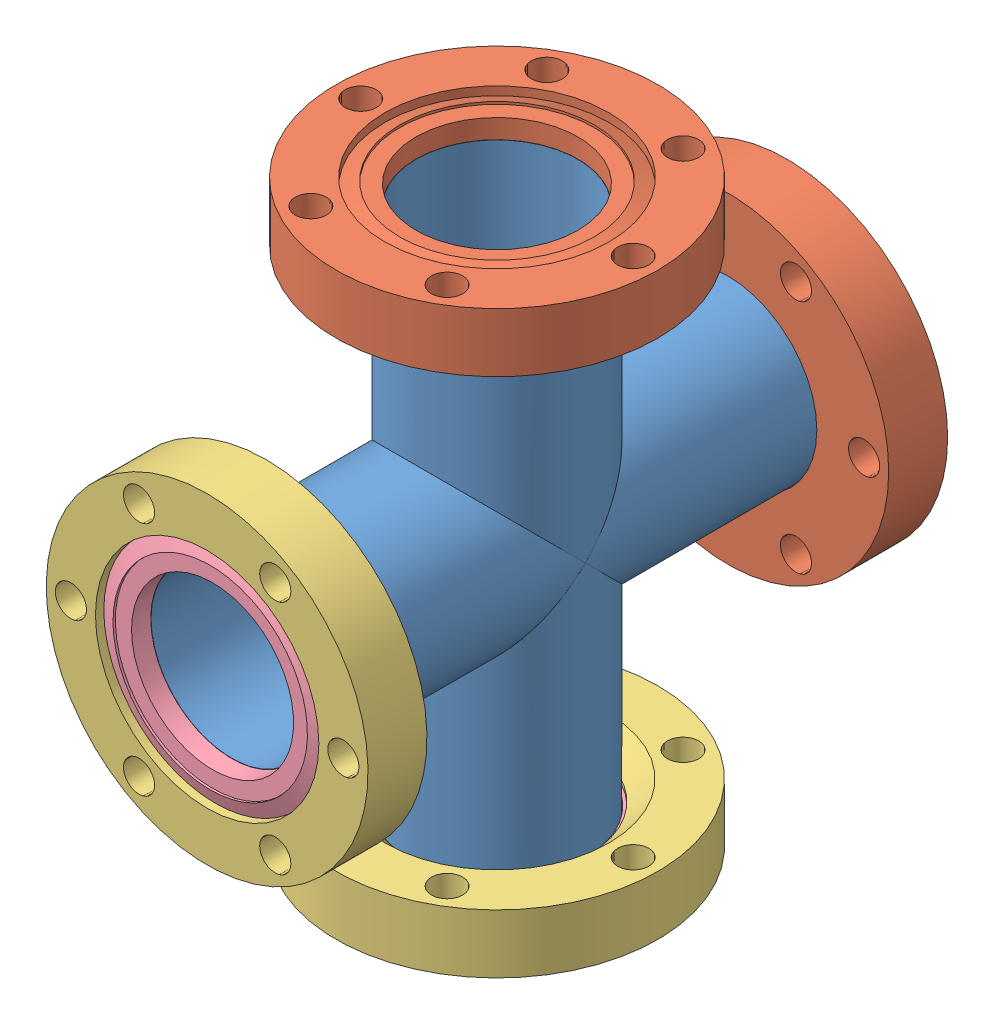
SolidWorks assembly Ion Gauge Nipple, configuration Default. Lengths in mm.
Overall size (69.34 124.92 124.92).
10 component instances, 4 part files, 0 mates.
Components (placement in the parent):
- 405002 P1_405002-001-1: 405002 P1_405002-001 [Default] at origin size (38.83 38.83 115)
- 405002 P1_405002-001-2: 405002 P1_405002-001 [Default] at (0 -57.15 57.15) x (1 0 0) z (0 1 0) size (38.83 38.83 115)
- 405002 P2_110014 (2.75 X 1.5 NR)_1-1: 405002 P2_110014 (2.75 X 1.5 NR)_1 [Default] at (0 56.1086 57.15) x (0 1 0) z (1 0 0) size (12.7 69.34 69.34)
- 405002 P2_110014 (2.75 X 1.5 NR)_1-2: 405002 P2_110014 (2.75 X 1.5 NR)_1 [Default] at (0 0 1.0414) x (0 0 -1) z (1 0 0) size (12.7 69.34 69.34)
- 405002 P3_100014 (2.75 X 1.5 R)_1-1: 405002 P3_100014 (2.75 X 1.5 R)_1 [Default] at (0 0 119.6086) x (0 0 -1) z (1 0 0) size (12.7 69.34 69.34)
  - 405002 P4_100014 (2.75 X 1.5 REC)_1-1: 405002 P4_100014 (2.75 X 1.5 REC)_1 [Default] at origin size (12.7 69.34 69.34)
  - 405002 P5_100014 (2.75 X 1.5 INS)_1-1: 405002 P5_100014 (2.75 X 1.5 INS)_1 [Default] at (1.17 0 0) x (1 0 0) z (0 0.994423 -0.105464) size (6.96 48.1 48.1)
- 405002 P3_100014 (2.75 X 1.5 R)_1-2: 405002 P3_100014 (2.75 X 1.5 R)_1 [Default] at (0 -62.4586 57.15) x (0 1 0) z (-1 0 0) size (12.7 69.34 69.34)
  - 405002 P4_100014 (2.75 X 1.5 REC)_1-1: 405002 P4_100014 (2.75 X 1.5 REC)_1 [Default] at origin size (12.7 69.34 69.34)
  - 405002 P5_100014 (2.75 X 1.5 INS)_1-1: 405002 P5_100014 (2.75 X 1.5 INS)_1 [Default] at (1.17 0 0) x (1 0 0) z (0 0.994423 -0.105464) size (6.96 48.1 48.1)
